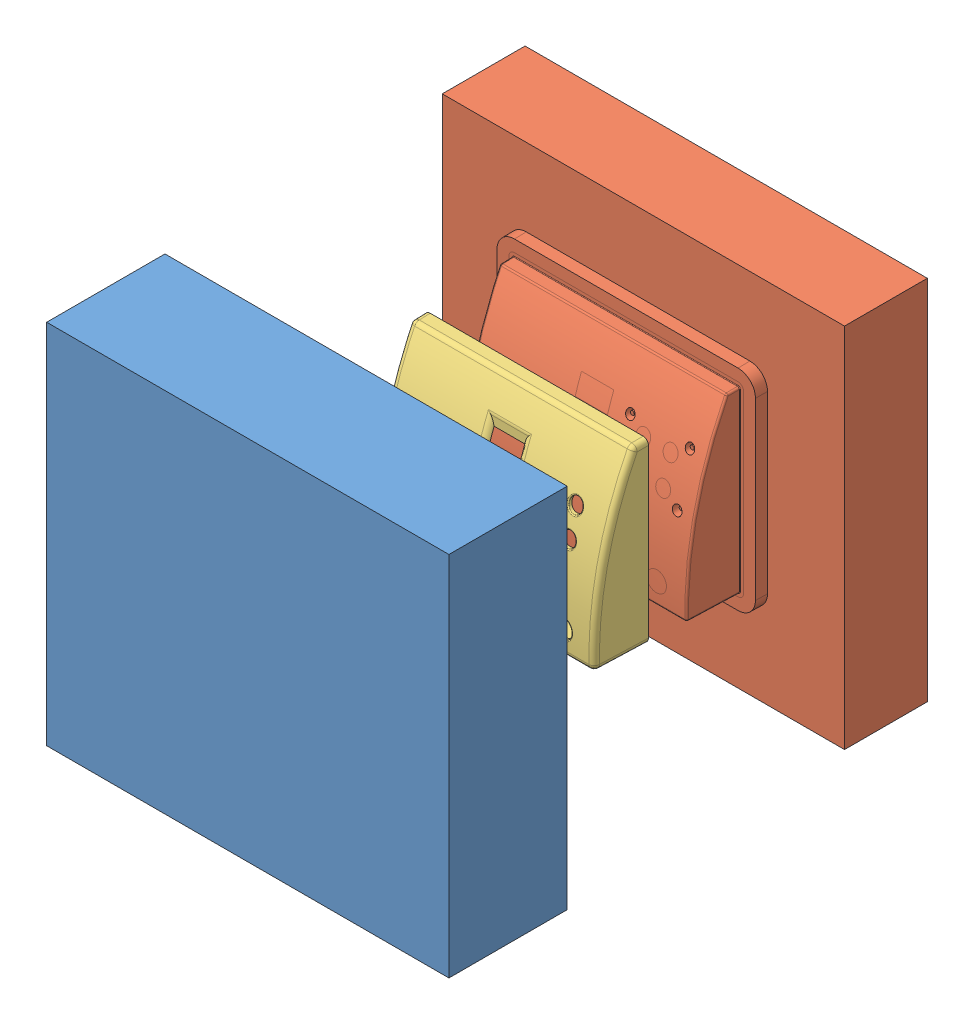
SolidWorks assembly Assem1, configuration Default. Lengths in mm.
Overall size (340 310 404.36).
3 component instances, 3 part files, 3 mates.
Components (placement in the parent):
- face-cavity-1: face-cavity [Default] at origin size (340 310 100.01)
- face-core-1: face-core [Default] at (0 0 -74.3589) size (340 310 124.35)
- new_face-1: new_face [Default] at origin size (189 150 45.18)
Mates (geometry in assembly coordinates):
- Coincident2: coincident aligned: plane of face-cavity-1 through (-260 -230 248.6686) normal (-1 0 0); plane of face-core-1 through (-260 -230 14.3097) normal (-1 0 0)
- Coincident3: coincident aligned: plane of face-cavity-1 through (80 -230 248.6686) normal (0 -1 0); plane of face-core-1 through (80 -230 14.3097) normal (0 -1 0)
- Coincident4: coincident aligned: plane of face-cavity-1 through (80 -230 248.6686) normal (1 0 0); plane of face-core-1 through (80 -230 14.3097) normal (1 0 0)
